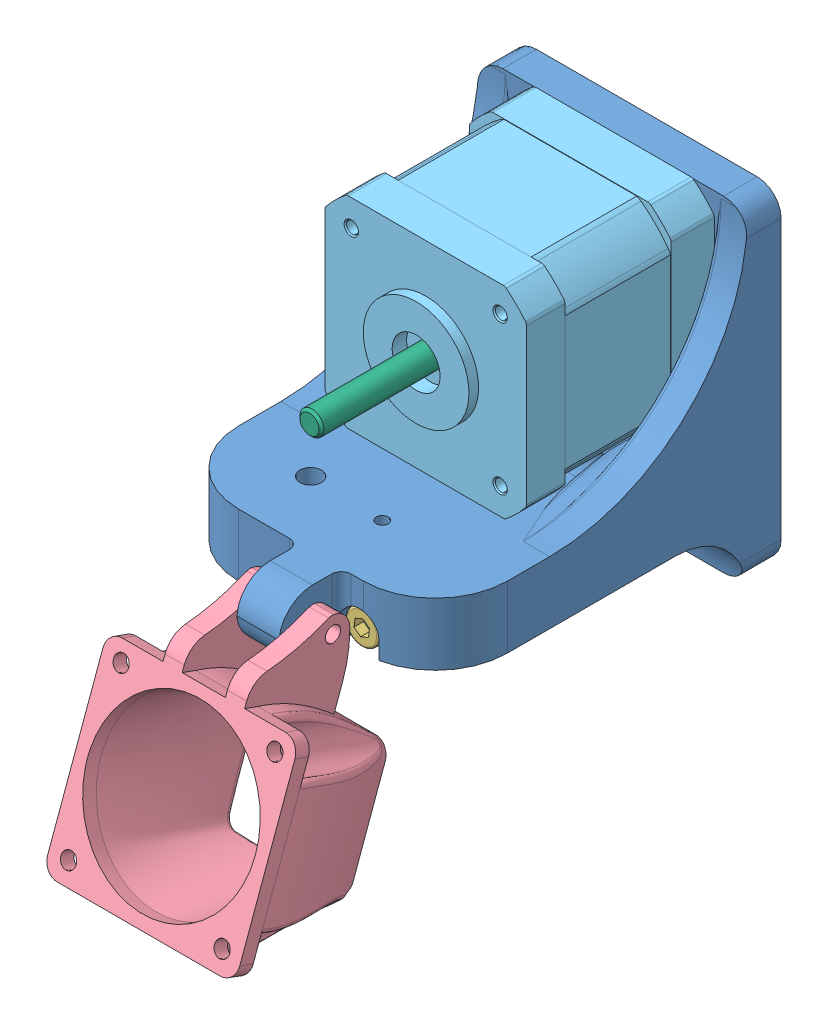
SolidWorks assembly DD1support, configuration Default. Lengths in mm.
Overall size (55.98 115.8 123.55).
14 component instances, 6 part files, 25 mates.
Components (placement in the parent):
- DD1support-1: DD1support [Default] at origin size (55.98 81.92 84.98)
- Hex nut-1: Hex nut [M4 Hex Nut] at (-11.5 3.8 0) size (7 8.08 3.2)
- Hex nut-5: Hex nut [M4 Hex Nut] at (11.5 3.8 0) size (7 8.08 3.2)
- Hex nut-8: Hex nut [M4 Hex Nut] at (-11.4063 -28.7 51.6) x (1 0 0) z (0 -1 0) size (7 8.08 3.2)
- Hex nut-9: Hex nut [M4 Hex Nut] at (-4.1461 -24.8 38.6431) size (7 8.08 3.2)
- Hex nut-10: Hex nut [M4 Hex Nut] at (12.1461 -24.8 38.6431) x (0.983219 -0.182428 0) z (0 0 1) size (7 8.08 3.2)
- Socket head cap screw-1: Socket head cap screw [M4x15] at (-4.1461 -24.8 64.5) x (0 0 -1) z (-0.956022 -0.293294 0) size (19 7 7)
- Socket head cap screw-3: Socket head cap screw [M4x15] at (12.1461 -24.8 64.5) x (0 0 -1) z (0.382249 -0.924059 0) size (19 7 7)
- Hex nut-11: Hex nut [M4 Hex Nut] at (-11.5 -19.2 0) size (7 8.08 3.2)
- Hex nut-12: Hex nut [M4 Hex Nut] at (11.5 -19.2 0) size (7 8.08 3.2)
- FUN-DUCT-0.1-1: FUN-DUCT-0.1 [Default] at (4.0244 -45.3084 96.0105) x (-1 0 0) z (0 -0.34202 -0.939693) size (42.99 53.77 46.81)
- Stepper_motor_NEMA17 39mm-1: Stepper_motor_NEMA17 39mm [Default] at (0.0671 5.3 41.1) x (1 0 0) z (0 -1 0) size (42 63.3 42)
  - Stator-1: Stator [Default] at origin size (42 41.1 42)
  - Rotor-1: Rotor [Default] x (0.508449 0 0.861092) z (-0.861092 0 0.508449) size (21 60.8 21)
Mates (geometry in assembly coordinates):
- Concentric1: concentric aligned: cylinder of DD1support-1 through (-11.5 3.8 -7) axis (0 0 1) radius 2; cylinder of Hex nut-1 through (-11.5 3.8 -3.2) axis (0 0 1) radius 1.65
- Concentric2: concentric aligned: cylinder of DD1support-1 through (-11.5 -11.5 -7) axis (0 0 1) radius 2; cylinder of ? through (-11.5 -11.5 -3.2) axis (0 0 1) radius 1.65
- Concentric3: concentric aligned: cylinder of DD1support-1 through (11.5 -11.5 -7) axis (0 0 1) radius 2; cylinder of ? through (11.5 -11.5 -3.2) axis (0 0 1) radius 1.65
- Concentric4: concentric aligned: cylinder of DD1support-1 through (11.5 3.8 -7) axis (0 0 1) radius 2; cylinder of Hex nut-5 through (11.5 3.8 -3.2) axis (0 0 1) radius 1.65
- Coincident3: coincident aligned: plane of DD1support-1 through (0 0 0) normal (0 0 1); plane of Hex nut-1 through (-11.5 7.8415 0) normal (0 0 1)
- Coincident4: coincident aligned: plane of DD1support-1 through (0 0 0) normal (0 0 1); plane of Hex nut-5 through (11.5 7.8415 0) normal (0 0 1)
- Coincident5: coincident aligned: plane of DD1support-1 through (0 0 0) normal (0 0 1); plane of ? through (-11.5 -7.4585 0) normal (0 0 1)
- Coincident6: coincident aligned: plane of DD1support-1 through (0 0 0) normal (0 0 1); plane of ? through (11.5 -7.4585 0) normal (0 0 1)
- Concentric5: concentric anti-aligned: cylinder of DD1support-1 through (-11.4063 -35.064 51.6) axis (0 1 0) radius 2.25; cylinder of Hex nut-8 through (-11.4063 -25.5 51.6) axis (0 -1 0) radius 1.65
- Coincident7: coincident aligned: plane of DD1support-1 through (-28 -28.7 -64.4662) normal (0 -1 0); plane of Hex nut-8 through (-11.4063 -28.7 55.6415) normal (0 -1 0)
- Concentric6: concentric aligned: cylinder of DD1support-1 through (-4.1461 -24.8 38) axis (0 0 1) radius 1.65; cylinder of Hex nut-9 through (-4.1461 -24.8 35.4431) axis (0 0 1) radius 1.65
- Coincident8: coincident anti-aligned: plane of DD1support-1 through (-7.9 -19.7 38.6431) normal (0 0 -1); plane of Hex nut-9 through (-4.1461 -20.7585 38.6431) normal (0 0 1)
- Concentric7: concentric aligned: cylinder of DD1support-1 through (12.1461 -24.8 38) axis (0 0 1) radius 1.65; cylinder of Hex nut-10 through (12.1461 -24.8 35.4431) axis (0 0 1) radius 1.65
- Coincident9: coincident anti-aligned: plane of DD1support-1 through (8.3921 -19.7 38.6431) normal (0 0 -1); plane of Hex nut-10 through (12.8833 -20.8264 38.6431) normal (0 0 1)
- Concentric8: concentric aligned: cylinder of DD1support-1 through (-4.1461 -24.8 38) axis (0 0 1) radius 1.65; cylinder of Socket head cap screw-1 through (-4.1461 -24.8 96.25) axis (0 0 1) radius 2
- Coincident10: coincident anti-aligned: plane of DD1support-1 through (-4.1461 -24.8 60.5) normal (0 0 1); plane of Socket head cap screw-1 through (-3.1195 -28.1461 60.5) normal (0 0 -1)
- Concentric9: concentric aligned: cylinder of DD1support-1 through (12.1461 -24.8 38) axis (0 0 1) radius 1.65; cylinder of Socket head cap screw-3 through (12.1461 -24.8 96.25) axis (0 0 1) radius 2
- Coincident11: coincident anti-aligned: plane of DD1support-1 through (12.1461 -24.8 60.5) normal (0 0 1); plane of Socket head cap screw-3 through (15.3803 -23.4621 60.5) normal (0 0 -1)
- Concentric10: concentric aligned: cylinder of DD1support-1 through (-11.5 -19.2 -12.6569) axis (0 0 1) radius 2; cylinder of Hex nut-11 through (-11.5 -19.2 -3.2) axis (0 0 1) radius 1.65
- Coincident12: coincident aligned: plane of DD1support-1 through (0 0 0) normal (0 0 1); plane of Hex nut-11 through (-11.5 -15.1585 0) normal (0 0 1)
- Parallel1: parallel anti-aligned: plane of DD1support-1 through (-15.094 -17.125 -4.5) normal (1 0 0); plane of Hex nut-11 through (-15 -17.1793 -3.2) normal (-1 0 0)
- Concentric11: concentric aligned: cylinder of DD1support-1 through (11.5 -19.2 -12.6569) axis (0 0 1) radius 2; cylinder of Hex nut-12 through (11.5 -19.2 -3.2) axis (0 0 1) radius 1.65
- Coincident14: coincident aligned: plane of DD1support-1 through (0 0 0) normal (0 0 1); plane of Hex nut-12 through (11.5 -15.1585 0) normal (0 0 1)
- Coincidente1: coincident anti-aligned: plane of DD1support-1 through (0 0 0) normal (0 0 1); plane of Stepper_motor_NEMA17 39mm-1/Stator-1 through (26.7671 5.3 0) normal (0 0 -1)
- Coincidente2: coincident anti-aligned: plane of DD1support-1 through (-28 -15.7 -64.4662) normal (0 1 0); plane of Stepper_motor_NEMA17 39mm-1/Stator-1 through (-20.9329 -15.7 0) normal (0 -1 0)
